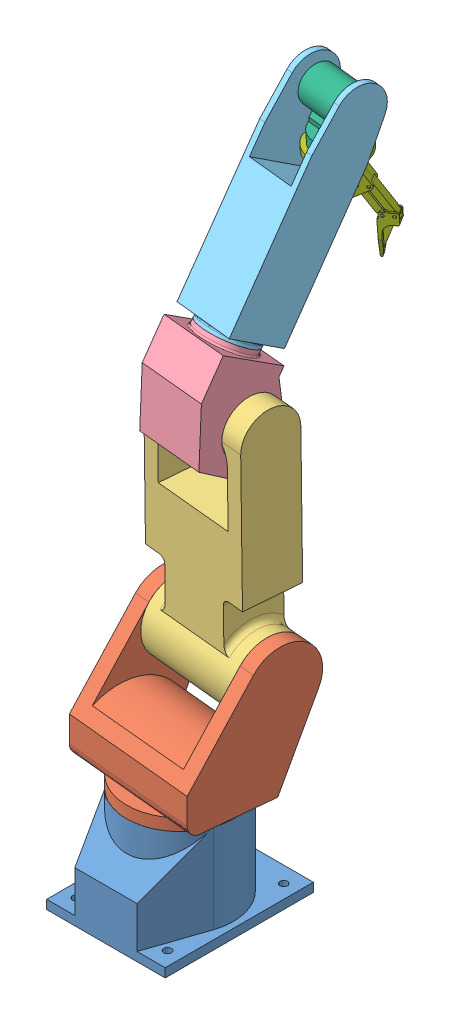
SolidWorks assembly Assem1, configuration Default. Lengths in mm.
Overall size (241.03 1131.04 452.08).
7 component instances, 7 part files, 12 mates.
Components (placement in the parent):
- Part1-1: Part1 [Default] at origin size (200 165 250)
- Part2-1: Part2 [Default] at (-0.4116 236.1093 4.2731) x (0.095885 0 -0.995392) z (0.995392 0 0.095885) size (219.55 237.96 221)
- Part3-1: Part3 [Default] at (6.2634 693.4346 -65.0215) x (0.995392 0 0.095885) z (-0.095878 -0.012051 0.99532) size (182 457 120)
- Part4-1: Part4 [Default] at (2.3845 718.008 -24.7541) x (-0.04978 -0.854672 0.516776) z (-0.08195 0.519168 0.850734) size (163.16 111 150.41)
- Part5-1: Part5 [Default] at (22.8874 1070.0197 -237.5975) x (-0.102894 0.519053 0.848526) z (0.993446 0.010933 0.113779) size (98 359.65 100)
- Part6-1: Part6 [Default] at (22.8874 1070.0197 -237.5975) x (0.993446 0.010933 0.113779) z (-0.112951 -0.058747 0.991862) size (80 98.82 74)
- GRIPPER-2: GRIPPER [Default] at (25.7557 923.0259 -246.1852) x (0.85356 0.044695 -0.519074) z (0.520699 -0.039663 0.852818) size (145.24 162.87 90)
Mates (geometry in assembly coordinates):
- Coincident1: coincident anti-aligned: axis of Part1-1 through (150 0 165) axis (0 0 -1); axis of Part2-1 through (0 165 0) axis (0 1 0)
- Coincident2: coincident anti-aligned: plane of Part1-1 through (0 165 0) normal (0 1 0); plane of Part2-1 through (0 165 0) normal (0 -1 0)
- Coincident3: coincident anti-aligned: axis of Part2-1 through (-78.4376 342.96 -77.4239) axis (-0.995392 0 -0.095885); axis of Part3-1 through (-78.4376 342.96 -77.4239) axis (0.995392 0 0.095885)
- Coincident4: coincident anti-aligned: plane of Part2-1 through (91.7745 342.96 -61.0276) normal (-0.995392 0 -0.095885); plane of Part3-1 through (91.7745 342.96 -61.0276) normal (0.995392 0 0.095885)
- Coincident5: coincident aligned: axis of Part3-1 through (-84.3173 693.4346 -73.747) axis (0.995392 0 0.095885); axis of Part4-1 through (-48.9809 693.4346 -70.3431) axis (0.995392 0 0.095885)
- Coincident7: coincident anti-aligned: plane of Part3-1 through (61.5077 693.4346 -59.6999) normal (-0.995392 0 -0.095885); plane of Part4-1 through (61.5077 693.4346 -59.6999) normal (0.995392 0 0.095885)
- Coincident8: coincident anti-aligned: axis of Part4-1 through (7.0249 797.6786 -72.9268) axis (-0.04978 -0.854672 0.516776); axis of Part5-1 through (7.0249 797.6786 -72.9268) axis (0.04978 0.854672 -0.516776)
- Coincident9: coincident anti-aligned: plane of Part4-1 through (7.0249 797.6786 -72.9268) normal (0.04978 0.854672 -0.516776); plane of Part5-1 through (7.0249 797.6786 -72.9268) normal (-0.04978 -0.854672 0.516776)
- Coincident10: coincident aligned: axis of Part5-1 through (-26.7849 1069.4731 -243.2864) axis (0.993446 0.010933 0.113779); axis of Part6-1 through (-8.9029 1069.6699 -241.2384) axis (0.993446 0.010933 0.113779)
- Coincident11: coincident anti-aligned: plane of Part5-1 through (-17.2189 950.8622 -227.5236) normal (0.993446 0.010933 0.113779); plane of Part6-1 through (-16.8504 1069.5824 -242.1486) normal (-0.993446 -0.010933 -0.113779)
- Coincident16: coincident anti-aligned: circle of Part6-1; plane of GRIPPER-2 through (24.0937 1001.3227 -241.529) normal (-0.017528 0.998213 0.057127)
- Concentric2: concentric anti-aligned: circle of Part6-1; circle of GRIPPER-2
